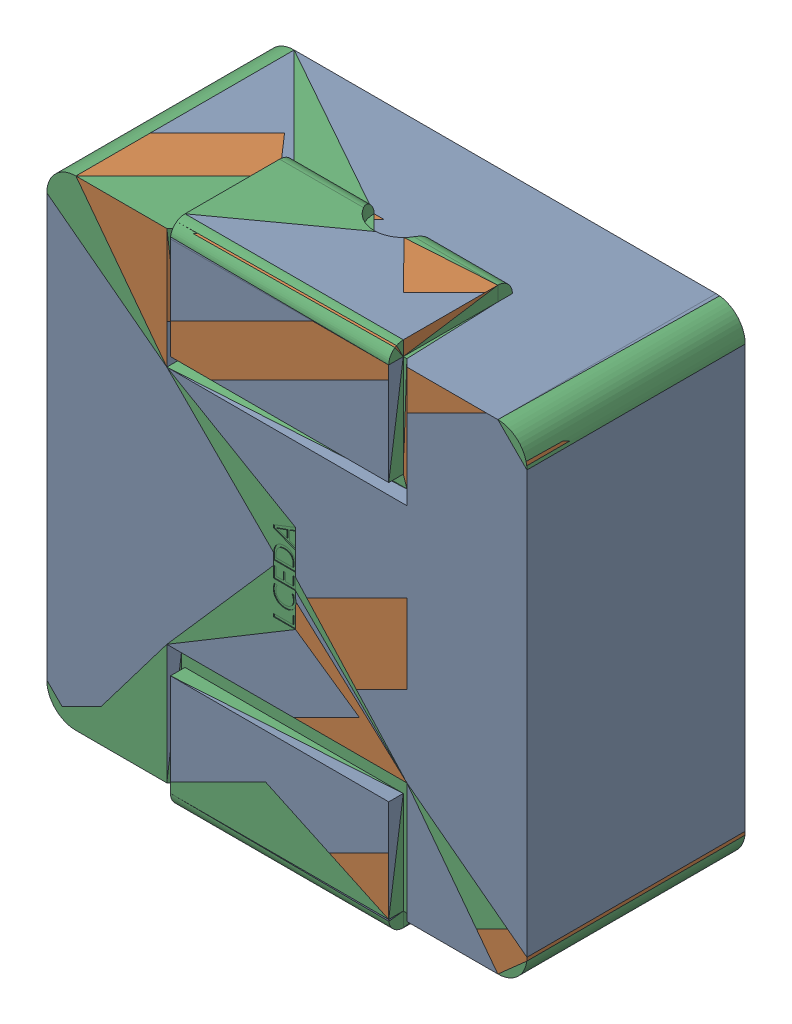
SolidWorks assembly L12, configuration Défaut. Lengths in mm.
Overall size (6.6 7.01 3.1).
3 component instances, 2 part files, 0 mates.
Components (placement in the parent):
- L7x6.8-1: L7x6.8 [Défaut] at (5.6258 -7.9313 -0.4818) x (0 -1 0) z (0 0 -1) size (7.01 6.6 3.1)
- L7x6.8-2: L7x6.8 [Défaut] at (5.6258 -7.9313 -0.4818) x (0 -1 0) z (0 0 -1) size (7.01 6.6 3.1)
- L7x6.8_1101-1: L7x6.8_1101 [Défaut] at (5.6258 -7.9313 -0.4818) x (0 -1 0) z (0 0 -1) size (7.01 6.6 3.1)
